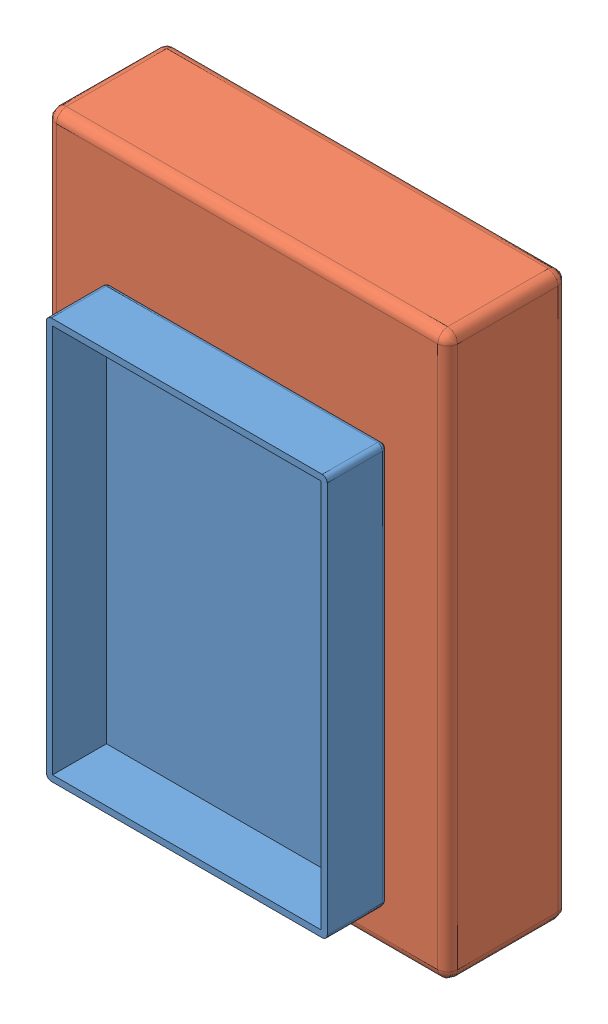
SolidWorks assembly Headrest, configuration Default. Lengths in mm.
Overall size (127 177.8 60.33).
3 component instances, 3 part files, 6 mates.
Components (placement in the parent):
- Headrest_Carbonfiber-1: Headrest_Carbonfiber [Default] at (-8.449 8.6291 -1.4041) size (88.9 127 19.05)
- Headrest_Foam-1: Headrest_Foam [Default] at (-8.449 21.3291 -39.5041) size (127 177.8 38.1)
- PSU logo-1: PSU logo [Default] at (-8.449 21.3291 -39.5041) x (-1 0 0) z (0 0 -1) size (102.58 102.58 3.17)
Mates (geometry in assembly coordinates):
- Coincident1: coincident anti-aligned: plane of Headrest_Carbonfiber-1 through (36.001 -54.8709 -1.4041) normal (0 0 -1); plane of Headrest_Foam-1 through (55.051 -67.5709 -1.4041) normal (0 0 1)
- Coincident2: coincident aligned: plane of Headrest_Carbonfiber-1 through (-8.449 8.6291 -1.4041) normal (1 0 0); plane of Headrest_Foam-1 through (-8.449 21.3291 -39.5041) normal (1 0 0)
- Coincident3: coincident anti-aligned: plane of Headrest_Foam-1 through (55.051 -67.5709 -39.5041) normal (0 0 -1); plane of PSU logo-1 through (-40.199 21.3291 -39.5041) normal (0 0 1)
- Coincident4: coincident aligned: plane of Headrest_Foam-1 through (-8.449 21.3291 -39.5041) normal (0 1 0); plane of PSU logo-1
- Coincident5: coincident anti-aligned: plane of Headrest_Foam-1 through (-8.449 21.3291 -39.5041) normal (1 0 0); plane of PSU logo-1 through (-8.449 21.3291 -39.5041) normal (-1 0 0)
- Distance1: distance = 12.7 mm aligned: plane of Headrest_Foam-1 through (-71.949 -67.5709 -1.4041) normal (0 -1 0); plane of Headrest_Carbonfiber-1 through (-52.899 -54.8709 17.6459) normal (0 -1 0)
